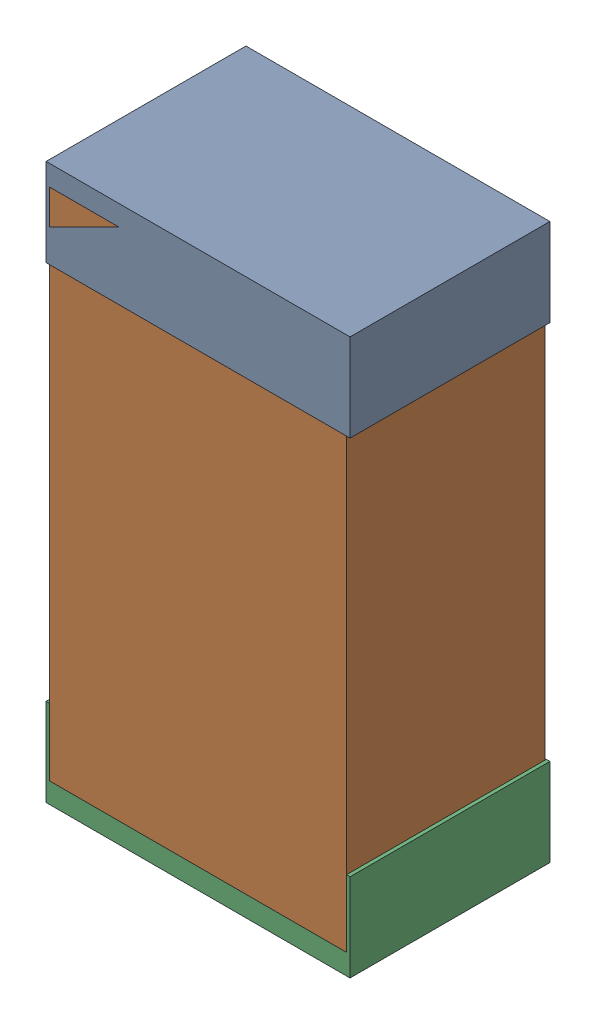
SolidWorks assembly R51Kanaloa_v2.0.0_Motor, configuration Default. Lengths in mm.
Overall size (1.3 2.38 0.85).
6 component instances, 2 part files, 0 mates.
Components (placement in the parent):
- 330415056-1: 330415056 [Default] at (92.964 154.67 -1.9574) size (1.3 0.38 0.85)
  - Extruded_2-1: Extruded_2 [Default] at origin size (1.3 0.38 0.85)
- 334787376-1: 334787376 [Default] at (92.964 153.67 -1.9524) size (1.27 2.2 0.85)
  - Extruded_16-1: Extruded_16 [Default] at origin size (1.27 2.2 0.85)
- 330415056-2: 330415056 [Default] at (92.964 152.67 -1.9574) size (1.3 0.38 0.85)
  - Extruded_2-1: Extruded_2 [Default] at origin size (1.3 0.38 0.85)
